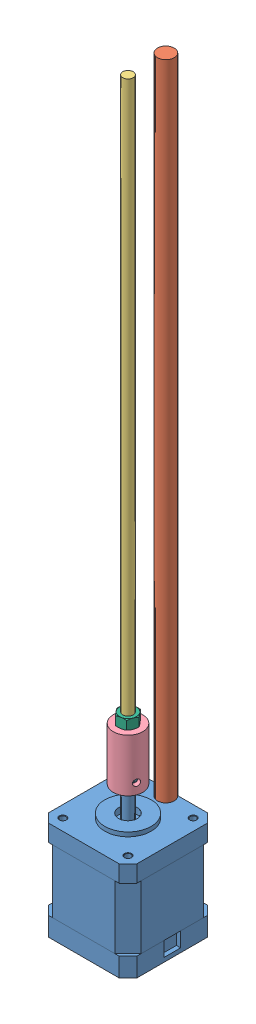
SolidWorks assembly z_motor, configuration Défaut. Lengths in mm.
Overall size (42 353 43).
7 component instances, 6 part files, 21 mates.
Components (placement in the parent):
- nema17-1: nema17 [Défaut] x (-1 0 0) z (0 -1 0) size (42 42 71)
- z_rod_smooth-1: z_rod_smooth [Défaut] at (0 0 -18) size (8 306 8)
- z_rod_threaded-1: z_rod_threaded [Défaut] at (0 24 0) x (-0.936635 0 -0.350308) z (0.350308 0 -0.936635) size (5 282 5)
- coupling-1: coupling [Défaut] at (0 39 0) x (-0.936635 0 -0.350308) z (-0.350308 0 0.936635) size (14 25 14)
- socket set screw oval point_am-1: socket set screw oval point_am [B18.3.6M - M3 x 0.5 x 2.5 Hex Socket Oval Pt. SS --N] at (-4.6832 19 -1.7515) x (0.936635 0 0.350308) z (-0.350308 0 0.936635) size (2.5 3 3)
- socket set screw oval point_am-2: socket set screw oval point_am [B18.3.6M - M3 x 0.5 x 2.5 Hex Socket Oval Pt. SS --N] at (4.6832 19 1.7515) x (-0.936635 0 -0.350308) z (-0.175154 -0.866025 0.468317) size (2.5 3 3)
- hex nut style 1_am-1: hex nut style 1_am [B18.2.4.1M - Hex nut, Style 1,  M5 x 0.8 --D-N] at (0 43.7 0) x (0.771693 0 -0.635995) z (0 1 0) size (8 9.24 4.7)
Mates (geometry in assembly coordinates):
- Coïncidente1: coincident: point of nema17-1; point of assembly
- Coaxiale1: concentric anti-aligned: cylinder of nema17-1 through (0 24 0) axis (0 -1 0) radius 2.5; line of z_rod_threaded-1 through (0 24 0) axis (0 1 0)
- Coïncidente4: coincident: point of nema17-1; point of assembly
- Coïncidente5: coincident anti-aligned: plane of nema17-1; plane of assembly through (0 0 0) normal (1 0 0)
- Coïncidente6: coincident anti-aligned: plane of nema17-1 through (0 0 0) normal (0 -1 0); plane of assembly through (0 0 0) normal (0 1 0)
- Coïncidente7: coincident anti-aligned: plane of nema17-1 through (0 24 0) normal (0 1 0); plane of z_rod_threaded-1 through (0 24 0) normal (0 -1 0)
- Coaxiale3: concentric anti-aligned: cylinder of nema17-1 through (0 24 0) axis (0 -1 0) radius 2.5; cylinder of coupling-1 through (0 13.999 0) axis (0 1 0) radius 2.5
- Distance1: distance = 12 mm anti-aligned: plane of coupling-1 through (0 14 0) normal (0 -1 0); plane of nema17-1 through (0 2 0) normal (0 1 0)
- Coïncidente10: coincident anti-aligned: plane of z_rod_threaded-1 through (0 24 0) normal (0.350308 0 -0.936635); plane of coupling-1 through (0 39 0) normal (-0.350308 0 0.936635)
- Coaxiale4: concentric aligned: cylinder of coupling-1 through (6.5564 19 2.4522) axis (-0.936635 0 -0.350308) radius 1.5; cylinder of socket set screw oval point_am-1 through (-16.5784 19 -6.2005) axis (-0.936635 0 -0.350308) radius 1.5
- Tangent1: tangent anti-aligned: cylinder of nema17-1 through (0 24 0) axis (0 -1 0) radius 2.5; sphere of socket set screw oval point_am-1
- Coaxiale6: concentric anti-aligned: cylinder of coupling-1 through (6.5564 19 2.4522) axis (-0.936635 0 -0.350308) radius 1.5; cylinder of socket set screw oval point_am-2 through (16.5784 19 6.2005) axis (0.936635 0 0.350308) radius 1.5
- Tangent2: tangent anti-aligned: cylinder of nema17-1 through (0 24 0) axis (0 -1 0) radius 2.5; sphere of socket set screw oval point_am-2
- Parallèle2: parallel aligned: line of socket set screw oval point_am-2 through (4.5315 19.75 2.1571) axis (0.350308 0 -0.936635); line of socket set screw oval point_am-1 through (-4.8349 19.75 -1.346) axis (0.350308 0 -0.936635)
- Parallèle3: parallel anti-aligned: line of socket set screw oval point_am-2 through (4.5315 19.75 2.1571) axis (0.350308 0 -0.936635); line of coupling-1 through (-3.4458 14 -6.0932) axis (-0.350308 0 0.936635)
- Coaxiale7: concentric anti-aligned: cone of coupling-1 through (0 38.5 0) axis (0 -1 0); cylinder of hex nut style 1_am-1 through (0 18.6625 0) axis (0 1 0) radius 2.5
- Coïncidente13: coincident anti-aligned: plane of coupling-1 through (0 39 0) normal (0 1 0); plane of hex nut style 1_am-1 through (-6.1735 39 5.088) normal (0 -1 0)
- Parallèle4: parallel aligned: plane of coupling-1 through (-5.0221 24 -1.8783) normal (-0.936635 0 -0.350308); plane of hex nut style 1_am-1 through (-2.9375 39 -3.5643) normal (-0.936635 0 -0.350308)
- Coïncidente14: coincident anti-aligned: plane of nema17-1 through (0 0 0) normal (0 1 0); plane of z_rod_smooth-1 through (0 0 -18) normal (0 -1 0)
- Coïncidente15: coincident anti-aligned: plane of nema17-1; plane of z_rod_smooth-1 through (0 0 -18) normal (1 0 0)
- Distance2: distance = 11.5 mm: cylinder of z_rod_smooth-1 through (0 306 -18) axis (0 -1 0) radius 4; cylinder of nema17-1 through (0 24 0) axis (0 -1 0) radius 2.5
